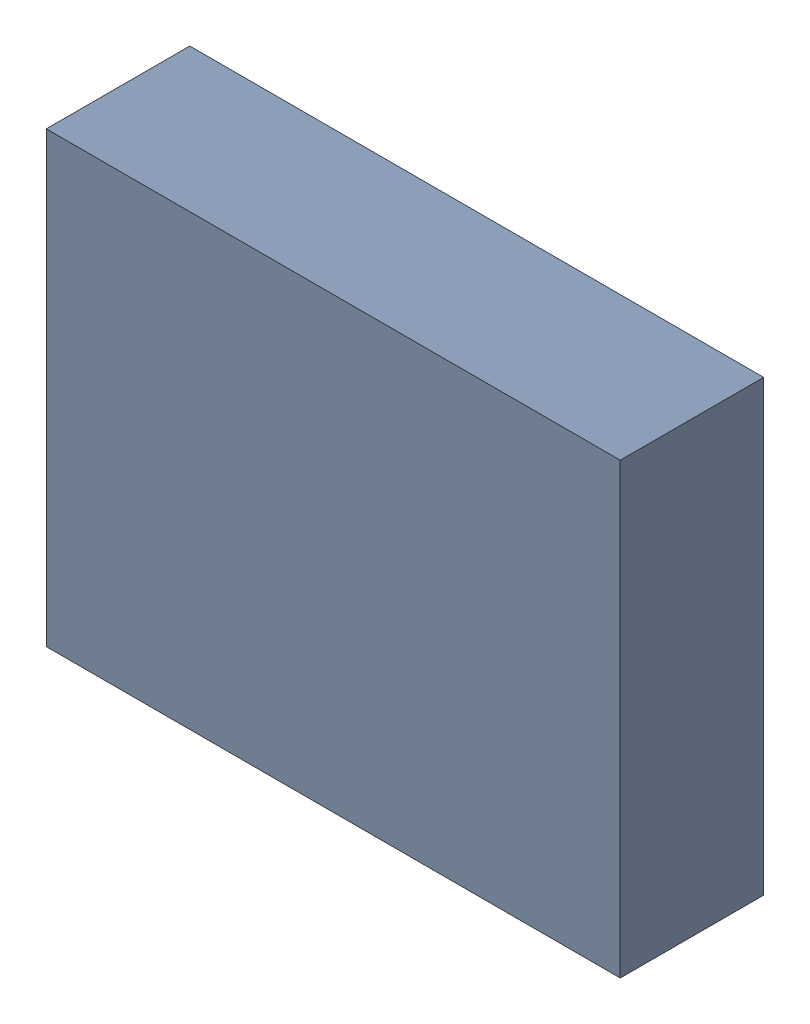
SolidWorks assembly X_TDA_TDA4, configuration Standard. Lengths in mm.
Overall size (3.2 2.5 0.8).
2 component instances, 1 part files, 0 mates.
Components (placement in the parent):
- 885545504-1: 885545504 [Standard] at (0.38 -41.99 0) size (3.2 2.5 0.8)
  - Extruded_6-1: Extruded_6 [Standard] at origin size (3.2 2.5 0.8)
